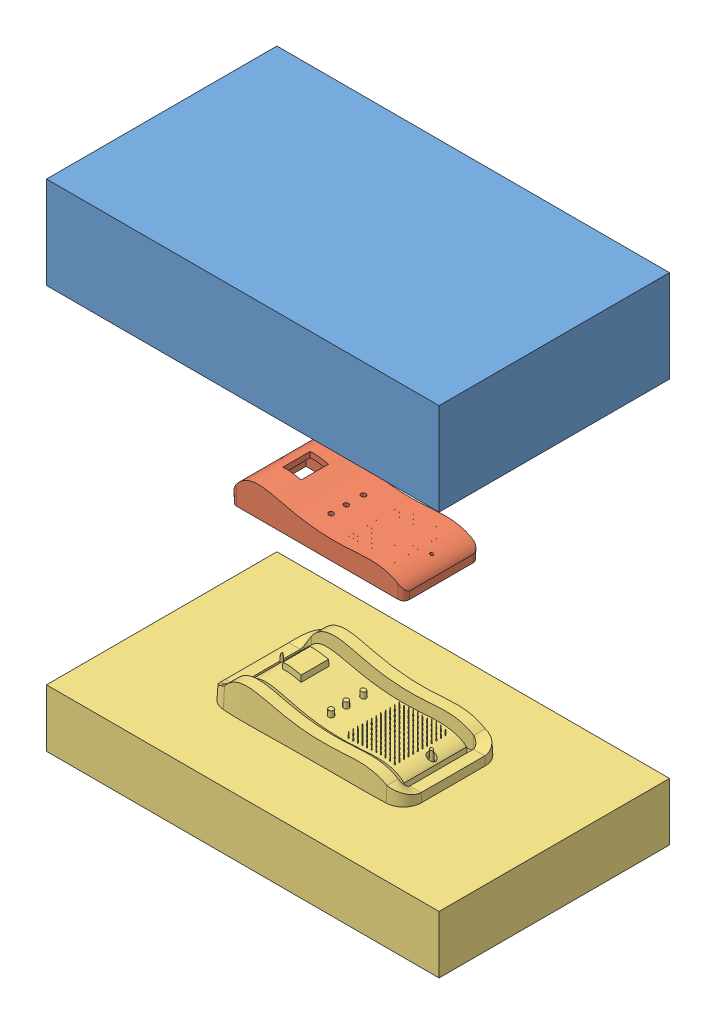
SolidWorks assembly Assem4, configuration Default. Lengths in mm.
Overall size (340.57 430 199.89).
3 component instances, 3 part files, 7 mates.
Components (placement in the parent):
- Body1-1: Body1 [Default] at (32.6972 -471.2965 220.9429) size (340.57 80.02 199.89)
- Body3-1: Body3 [Default] at (35.3007 -547.1422 223.5464) size (151.87 42.41 86.82)
- Save Bodies1[2]-1: Save Bodies1[2] [Default] at (32.6972 -621.2965 220.9429) size (340.57 89.26 199.89)
Mates (geometry in assembly coordinates):
- Coincident1: coincident aligned: plane of Body1-1 through (305.0909 298.7035 322.6864) normal (1 0 0); plane of Save Bodies1[2]-1 through (305.0909 -1.2965 322.6864) normal (1 0 0)
- Coincident2: coincident aligned: plane of Body1-1 through (-35.4801 298.7035 322.6864) normal (0 0 1); plane of Save Bodies1[2]-1 through (-35.4801 -1.2965 322.6864) normal (0 0 1)
- Coincident3: coincident anti-aligned: plane of Body3-1 through (207.9789 198.7035 256.0464) normal (0 -0.017452 0.999848); plane of Save Bodies1[2]-1 through (205.3754 49.5492 253.4429) normal (0 0.017452 -0.999848)
- Coincident4: coincident anti-aligned: plane of Body3-1 through (207.9789 198.7035 191.0464) normal (0.999848 -0.017452 0); plane of Save Bodies1[2]-1 through (205.3754 49.5492 188.4429) normal (-0.999848 0.017452 0)
- LimitDistance1: limit distance = 149.1543 mm anti-aligned: plane of Body3-1 through (207.9789 198.7035 191.0364) normal (0 -1 0); plane of Save Bodies1[2]-1 through (205.3754 49.5492 188.4329) normal (0 1 0)
- LimitDistance3: limit distance = 300 mm anti-aligned: plane of Body1-1 through (134.8054 348.7035 222.7392) normal (0 -1 0); plane of Save Bodies1[2]-1 through (134.8054 48.7035 222.7392) normal (0 1 0)
- LimitDistance4: limit distance = 150 mm aligned: plane of Body3-1 through (207.9789 198.7035 191.0364) normal (0 -1 0); plane of Body1-1 through (134.8054 348.7035 222.7392) normal (0 -1 0)
